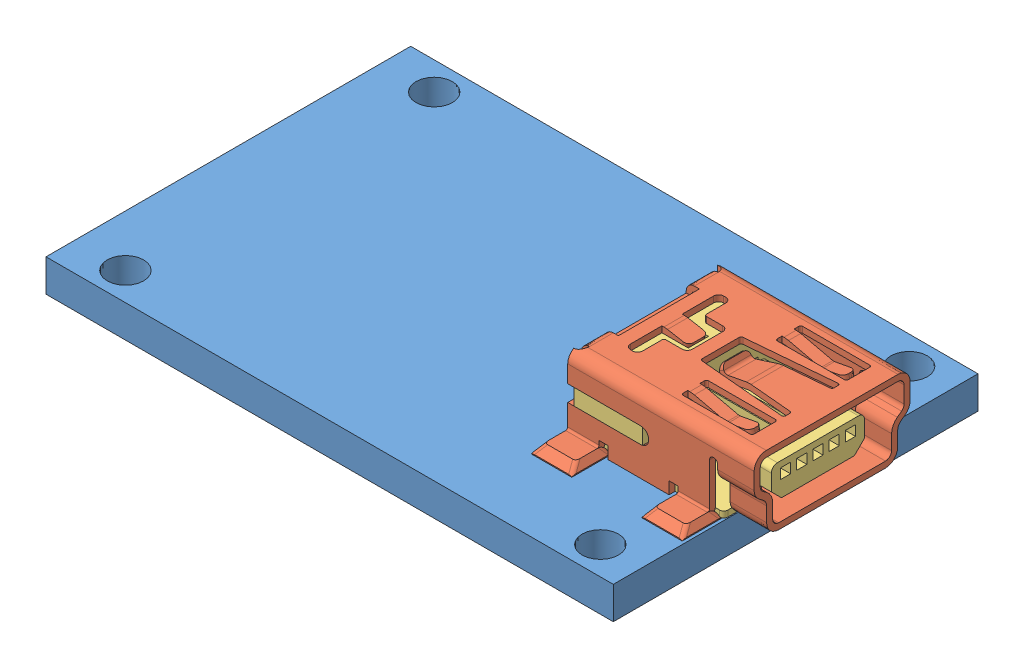
SolidWorks assembly Lithum battery charger and Output, configuration Default. Lengths in mm.
Overall size (29.8 5.35 18).
5 component instances, 4 part files, 3 mates.
Components (placement in the parent):
- Li2-Board-1: Li2-Board [Default] at origin size (28 1.6 18)
- Li2-MINIUSB - MEASURED-1: Li2-MINIUSB - MEASURED [Default] at (31.38 1.65 -7.62) x (0 0 1) z (-1 0 0) size (10.9 4.8 9.4)
  - Li2-MINIUSBSHELL-1: Li2-MINIUSBSHELL [Default] at origin size (10.9 3.75 9.4)
  - Li2-MINIUSBCORE-1: Li2-MINIUSBCORE [Default] at (0 0 6.7) x (-1 0 0) z (0 0 -1) size (7.7 4.5 8.2)
  - MINI USB SOLDER-1: MINI USB SOLDER [Default] at (0 -0.05 -0.4) x (-1 0 0) z (0 0 -1) (suppressed, hidden)
Mates (geometry in assembly coordinates):
- Distance27: distance = 7.62 mm aligned: plane of MINIUSB - MEASURED-1 through (31.38 1.65 -7.62) normal (0 0 1); plane of assembly through (0 0 0) normal (0 0 1)
- Distance28: distance = 0.4 mm anti-aligned: plane of Li2-Board-1 through (31.78 1.6 -16.62) normal (1 0 0); plane of MINIUSB - MEASURED-1/MINIUSBSHELL-1 through (31.38 1.65 -7.62) normal (-1 0 0)
- Coincident56: coincident anti-aligned: plane of Li2-Board-1 through (0 1.6 0) normal (0 1 0); plane of Li2-MINIUSB - MEASURED-1/Li2-MINIUSBSHELL-1 through (31.38 1.6 -7.62) normal (0 -1 0)
